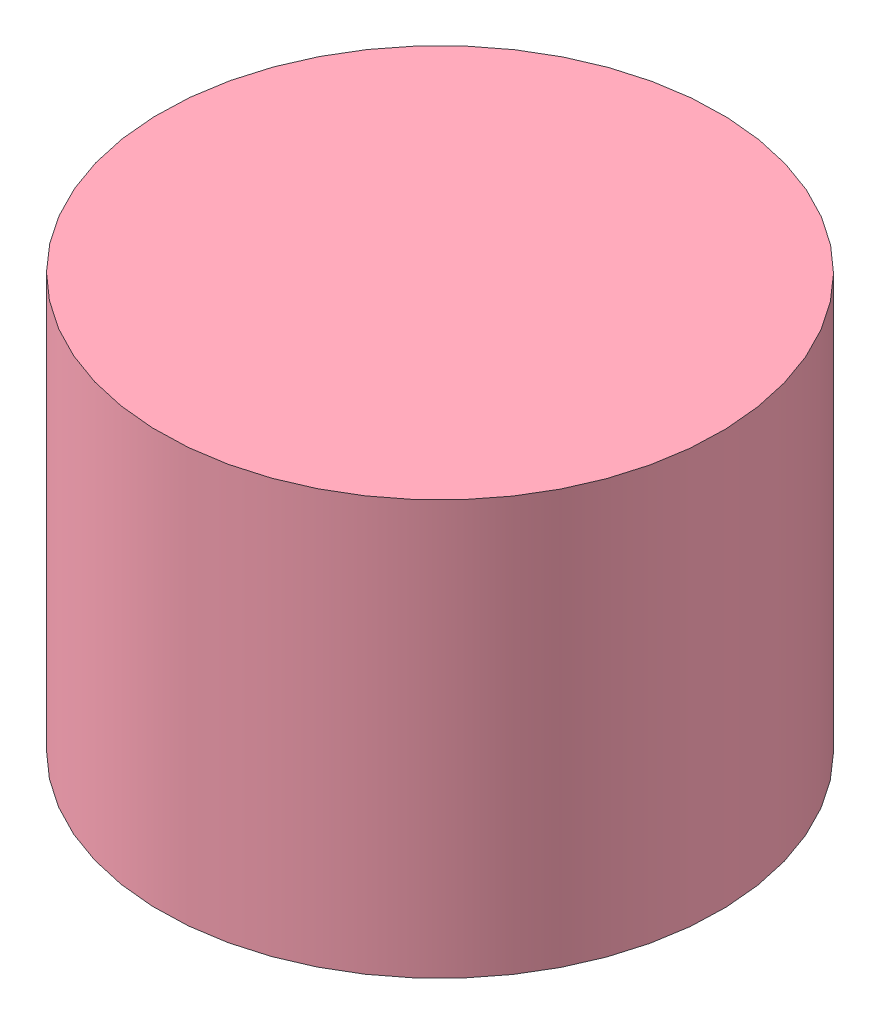
SolidWorks assembly EnsamblajeBatidor, configuration Predeterminado. Lengths in mm.
Overall size (111.35 67 111.35).
5 component instances, 5 part files, 9 mates.
Components (placement in the parent):
- SoporteMotor-1: SoporteMotor [Predeterminado] at (-12.199 19.6116 47) size (31.8 22 31.8)
- Motor-1: Motor [Predeterminado] at (-12.199 29.1116 47) x (0.949438 0 -0.313954) z (0.313954 0 0.949438) size (30 47.9 30)
- SoporteImanes-1: SoporteImanes [Predeterminado] at (-12.199 72.0116 47) x (-0.28831 0 -0.957537) z (0.957537 0 -0.28831) size (50 5 50)
- TapaBatidor-1: TapaBatidor [Predeterminado] at (-12.199 15.0116 47) x (-0.276151 0 -0.961114) z (0.961114 0 -0.276151) size (90 67 90)
- BaseBatido-1: BaseBatido [Predeterminado] at (-12.199 19.6116 47) x (0.876966 0 0.480553) z (-0.480553 0 0.876966) size (81 4 81)
Mates (geometry in assembly coordinates):
- Concéntrica8: concentric: cylinder of assembly; cylinder of assembly; cylinder of Motor-1 through (-12.199 77.0116 47) axis (0 -1 0) radius 3.35; cylinder of SoporteImanes-1 through (-12.199 30.0116 47) axis (0 1 0) radius 3.5
- Coincidente6: coincident: plane of assembly; plane of assembly; plane of Motor-1 through (-12.199 72.0116 47) normal (0 1 0); plane of SoporteImanes-1 through (-12.199 72.0116 47) normal (0 -1 0)
- Concéntrica9: concentric: cylinder of assembly; cylinder of assembly; cylinder of SoporteMotor-1 through (-12.199 41.6116 47) axis (0 -1 0) radius 13.9; cylinder of Motor-1 through (-12.199 41.6116 47) axis (0 -1 0) radius 13.75
- Coincidente7: coincident: plane of assembly; plane of assembly; plane of SoporteMotor-1 through (-12.199 41.6116 47) normal (0 1 0); plane of Motor-1 through (-12.199 41.6116 47) normal (0 -1 0)
- Concéntrica10: concentric: cylinder of assembly; circle of assembly; cylinder of SoporteMotor-1 through (-12.199 41.6116 47) axis (0 -1 0) radius 15.9; circle of BaseBatido-1
- Concéntrica11: concentric: cylinder of assembly; cylinder of assembly; cylinder of SoporteMotor-1 through (-12.199 41.6116 47) axis (0 -1 0) radius 15.9; cylinder of TapaBatidor-1 through (-12.199 80.0116 47) axis (0 -1 0) radius 45
- Distancia1: distance = 5 mm: plane of assembly; plane of assembly; plane of SoporteImanes-1 through (-12.199 77.0116 47) normal (0 1 0); plane of TapaBatidor-1 through (-12.199 82.0116 47) normal (0 1 0)
- Concéntrica12: concentric: cylinder of assembly; cylinder of assembly; cylinder of SoporteMotor-1 through (-12.199 41.6116 47) axis (0 -1 0) radius 15.9; cylinder of BaseBatido-1 through (-12.199 11.6116 47) axis (0 1 0) radius 40.5
- Coincidente9: coincident: plane of assembly; plane of assembly; plane of SoporteMotor-1 through (-12.199 19.6116 47) normal (0 -1 0); plane of BaseBatido-1 through (-12.199 19.6116 47) normal (0 1 0)
